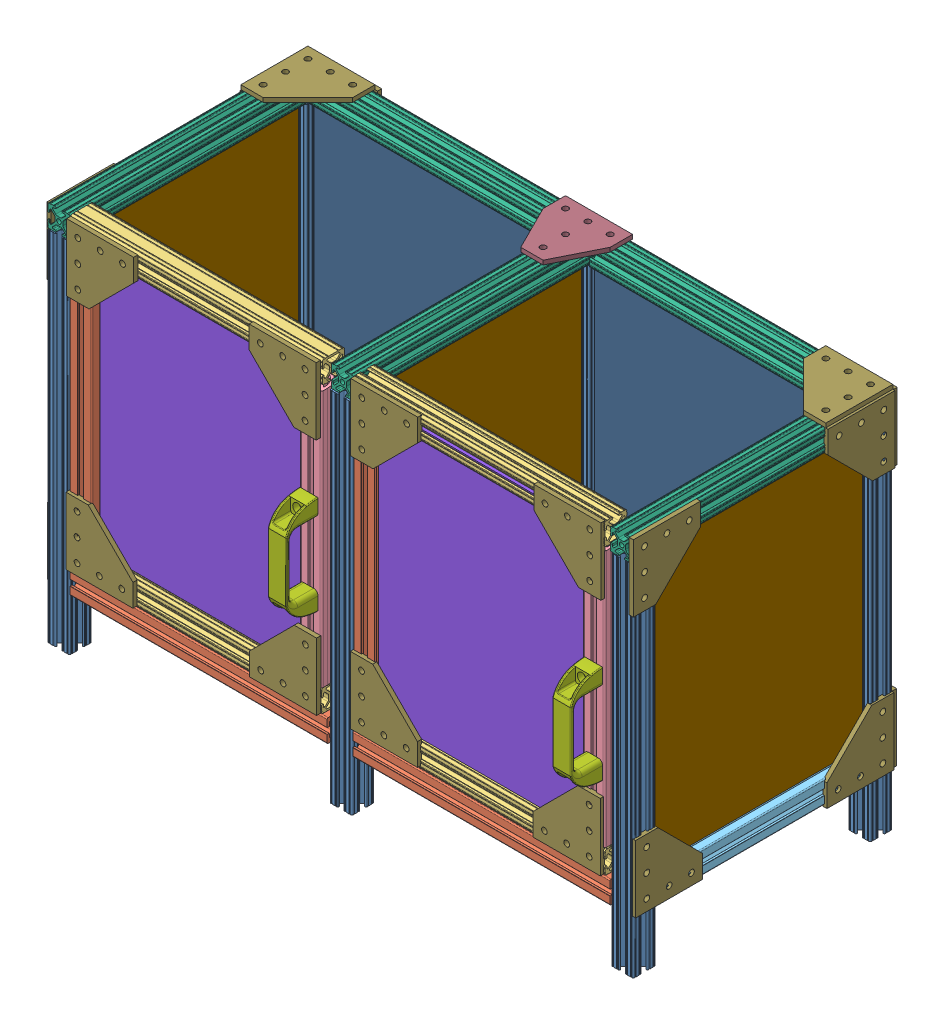
SolidWorks assembly Box_Ext_6_25_2024_Duplex, configuration Default. Lengths in mm.
Overall size (666.64 439.32 339.39).
68 component instances, 13 part files, 0 mates.
Components (placement in the parent):
- 1A_1D_16in47065T801_T-Slotted Framing rail-1: 1A_1D_16in47065T801_T-Slotted Framing rail [47065T801] at (-239.4342 265.817 193.973) x (0 0 1) z (0 1 0) size (25.4 25.4 406.4)
- 1A_1D_16in47065T801_T-Slotted Framing rail-2: 1A_1D_16in47065T801_T-Slotted Framing rail [47065T801] at (-240.0711 265.9257 462.8579) x (1 0 0) z (0 -1 0) size (25.4 25.4 406.4)
- 1A_1D_16in47065T801_T-Slotted Framing rail-3: 1A_1D_16in47065T801_T-Slotted Framing rail [47065T801] at (79.5241 264.9055 193.6515) x (1 0 0) z (0 -1 0) size (25.4 25.4 406.4)
- 1A_1D_16in47065T801_T-Slotted Framing rail-4: 1A_1D_16in47065T801_T-Slotted Framing rail [47065T801] at (79.0395 264.9055 462.2875) x (1 0 0) z (0 -1 0) size (25.4 25.4 406.4)
- 3A_3B_3C_11_5in6575N217_T-Slotted Framing Rail-1: 3A_3B_3C_11_5in6575N217_T-Slotted Framing Rail [6575N217] at (-80.5158 133.3354 462.6399) x (0 0 1) z (1 0 0) size (25.4 25.4 292.1)
- 5A_5B_11_25in_47065T846_T-Slotted Framing-1: 5A_5B_11_25in_47065T846_T-Slotted Framing [47065T846] at (-83.0751 159.6001 462.6399) x (0 0 1) z (-1 0 0) size (25.4 25.4 285.75)
- 3A_3B_3C_11_5in6575N217_T-Slotted Framing Rail-2: 3A_3B_3C_11_5in6575N217_T-Slotted Framing Rail [6575N217] at (-213.4294 321.0324 462.7499) x (1 0 0) z (0 -1 0) size (25.4 25.4 292.1)
- 6_11_5in6575N218_T-Slotted Framing Rail-1: 6_11_5in6575N218_T-Slotted Framing Rail [6575N218] at (46.9584 319.918 462.4695) x (0 1 0) z (1 0 0) size (292.1 25.4 25.4)
- 5A_5B_11_25in_47065T846_T-Slotted Framing-2: 5A_5B_11_25in_47065T846_T-Slotted Framing [47065T846] at (-83.4418 482.5282 462.8007) x (0 1 0) z (1 0 0) size (25.4 25.4 285.75)
- 2A_2B_9_5in6575N217_T-Slotted Framing Rail-1: 2A_2B_9_5in6575N217_T-Slotted Framing Rail [6575N217] at (78.5396 136.1503 326.476) size (25.4 25.4 241.3)
- 2A_2B_9_5in6575N217_T-Slotted Framing Rail-2: 2A_2B_9_5in6575N217_T-Slotted Framing Rail [6575N217] at (-239.3609 136.2243 327.8144) x (0 1 0) z (0 0 1) size (25.4 25.4 241.3)
- 3A_3B_3C_11_5in6575N217_T-Slotted Framing Rail-3: 3A_3B_3C_11_5in6575N217_T-Slotted Framing Rail [6575N217] at (-81.1923 133.366 194.3443) x (0 0.008727 0.999962) z (-1 0 0) size (25.4 25.4 292.1)
- 4A_4C_11_5in47065T801_T-Slotted Framing rail-1: 4A_4C_11_5in47065T801_T-Slotted Framing rail [47065T801] at (-240.0375 481.9511 327.6131) size (25.4 25.4 292.1)
- 4A_4C_11_5in47065T801_T-Slotted Framing rail-2: 4A_4C_11_5in47065T801_T-Slotted Framing rail [47065T801] at (77.9867 481.0907 328.468) size (25.4 25.4 292.1)
- 4A_4C_11_5in47065T801_T-Slotted Framing rail-3: 4A_4C_11_5in47065T801_T-Slotted Framing rail [47065T801] at (-80.1705 480.6089 194.2481) x (0 1 0) z (1 0 0) size (25.4 25.4 292.1)
- 47065T595_Red Plastic Pull Handle-1: 47065T595_Red Plastic Pull Handle [47065T595] at (47.7995 342.8306 476.5075) x (-1 0 0) z (0 0 1) size (21.11 112.11 36)
- pD-1: pD [Default] at (39.7962 478.6241 471.804) x (-1 0 0) z (0 -1 0) size (250.83 4.76 304.8)
- pA-1: pA [Default] at (80.357 148.7713 200.6755) x (0 1 0) z (0 0 1) size (317.5 4.76 254)
- pA-2: pA [Default] at (-240.7265 149.3164 198.8892) x (0 1 0) z (0 0 1) size (317.5 4.76 254)
- pB-3: pB [Default] at (-237.6602 138.9797 195.7037) x (0 1 0) z (1 0 0) size (330.2 4.76 304.8)
- pE-1: pE [Default] at (-227.8794 132.6636 204.9097) size (50.8 4.76 254)
- pE-2: pE [Default] at (-164.9525 130.5241 208.5576) size (50.8 4.76 254)
- pE-3: pE [Default] at (-102.4815 131.3886 208.1017) size (50.8 4.76 254)
- pE-4: pE [Default] at (-41.8346 135.1169 204.9097) size (50.8 4.76 254)
- pE-5: pE [Default] at (16.0764 135.6961 203.9977) size (50.8 4.76 254)
- 47065T267_T-Slotted Framing-5: 47065T267_T-Slotted Framing [47065T267] at (-225.7817 150.6545 476.5665) size (76.2 76.2 4.76)
- 47065T267_T-Slotted Framing-6: 47065T267_T-Slotted Framing [47065T267] at (-225.4278 495.4606 476.5665) x (1 0 0) z (0 0 -1) size (76.2 76.2 4.76)
- 47065T267_T-Slotted Framing-7: 47065T267_T-Slotted Framing [47065T267] at (58.1546 147.8233 476.5665) x (-1 0 0) z (0 0 -1) size (76.2 76.2 4.76)
- 47065T267_T-Slotted Framing-8: 47065T267_T-Slotted Framing [47065T267] at (58.8624 495.4606 476.5665) x (0 -1 0) z (0 0 -1) size (76.2 76.2 4.76)
- 47065T267_T-Slotted Framing-9: 47065T267_T-Slotted Framing [47065T267] at (91.7738 121.2891 181.2308) x (0 1 0) z (1 0 0) size (76.2 76.2 4.76)
- 47065T267_T-Slotted Framing-10: 47065T267_T-Slotted Framing [47065T267] at (91.7738 122.3717 474.8484) x (0 0 -1) z (1 0 0) size (76.2 76.2 4.76)
- 47065T267_T-Slotted Framing-11: 47065T267_T-Slotted Framing [47065T267] at (91.7738 493.9478 180.1367) x (0 0 1) z (1 0 0) size (76.2 76.2 4.76)
- 47065T267_T-Slotted Framing-12: 47065T267_T-Slotted Framing [47065T267] at (91.7738 495.7024 477.344) x (0 -1 0) z (1 0 0) size (76.2 76.2 4.76)
- 47065T267_T-Slotted Framing-14: 47065T267_T-Slotted Framing [47065T267] at (91.3964 120.9795 177.9621) x (-1 0 0) z (0 0 -1) size (76.2 76.2 4.76)
- 47065T267_T-Slotted Framing-16: 47065T267_T-Slotted Framing [47065T267] at (92.1046 493.9024 177.9621) x (-1 0 0) z (0 0 1) size (76.2 76.2 4.76)
- 4A_4C_11_5in47065T801_T-Slotted Framing rail-4: 4A_4C_11_5in47065T801_T-Slotted Framing rail [47065T801] at (-399.0464 482.3587 194.4736) x (0 0 -1) z (1 0 0) size (25.4 25.4 292.1)
- 4A_4C_11_5in47065T801_T-Slotted Framing rail-5: 4A_4C_11_5in47065T801_T-Slotted Framing rail [47065T801] at (-558.1373 482.8226 331.5399) size (25.4 25.4 292.1)
- 3A_3B_3C_11_5in6575N217_T-Slotted Framing Rail-4: 3A_3B_3C_11_5in6575N217_T-Slotted Framing Rail [6575N217] at (-398.4723 134.0137 195.5798) x (0 0 -1) z (-1 0 0) size (25.4 25.4 292.1)
- 3A_3B_3C_11_5in6575N217_T-Slotted Framing Rail-5: 3A_3B_3C_11_5in6575N217_T-Slotted Framing Rail [6575N217] at (-398.8921 134.4335 465.566) x (0 0 -1) z (-1 0 0) size (25.4 25.4 292.1)
- 2A_2B_9_5in6575N217_T-Slotted Framing Rail-3: 2A_2B_9_5in6575N217_T-Slotted Framing Rail [6575N217] at (-557.1339 134.4335 331.1914) x (1 0 0) z (0 0 -1) size (25.4 25.4 241.3)
- 1A_1D_16in47065T801_T-Slotted Framing rail-5: 1A_1D_16in47065T801_T-Slotted Framing rail [47065T801] at (-558.2613 266.406 196.6909) x (0 0 -1) z (0 1 0) size (25.4 25.4 406.4)
- 1A_1D_16in47065T801_T-Slotted Framing rail-6: 1A_1D_16in47065T801_T-Slotted Framing rail [47065T801] at (-558.2613 265.9621 465.316) x (0 0 1) z (0 1 0) size (25.4 25.4 406.4)
- 5A_5B_11_25in_47065T846_T-Slotted Framing-3: 5A_5B_11_25in_47065T846_T-Slotted Framing [47065T846] at (-402.1574 160.4493 465.566) x (0 0 1) z (-1 0 0) size (25.4 25.4 285.75)
- 3A_3B_3C_11_5in6575N217_T-Slotted Framing Rail-6: 3A_3B_3C_11_5in6575N217_T-Slotted Framing Rail [6575N217] at (-531.9495 322.4768 466.5987) x (-1 0 0) z (0 1 0) size (25.4 25.4 292.1)
- 6_11_5in6575N218_T-Slotted Framing Rail-2: 6_11_5in6575N218_T-Slotted Framing Rail [6575N218] at (-272.0186 319.0325 465.0526) x (0 -1 0) z (0 0 -1) size (292.1 25.4 25.4)
- 5A_5B_11_25in_47065T846_T-Slotted Framing-4: 5A_5B_11_25in_47065T846_T-Slotted Framing [47065T846] at (-402.3423 483.165 464.4355) x (0 0 1) z (1 0 0) size (25.4 25.4 285.75)
- pD-2: pD [Default] at (-274.4888 166.647 461.6473) x (-1 0 0) z (0 1 0) size (250.83 4.76 304.8)
- pA-3: pA [Default] at (-554.1224 464.9141 452.6716) x (0 -1 0) z (0 0 -1) size (317.5 4.76 254)
- pB-4: pB [Default] at (-552.971 143.2769 191.2421) x (0 1 0) z (1 0 0) size (330.2 4.76 304.8)
- pE-6: pE [Default] at (-546.4363 124.5592 202.1402) size (50.8 4.76 254)
- pE-7: pE [Default] at (-487.6728 124.5592 206.3376) size (50.8 4.76 254)
- pE-8: pE [Default] at (-425.971 124.5592 206.7574) size (50.8 4.76 254)
- pE-9: pE [Default] at (-365.5285 124.5592 205.9179) size (50.8 4.76 254)
- pE-10: pE [Default] at (-303.8268 125.4542 203.8192) size (50.8 4.76 254)
- 47065T595_Red Plastic Pull Handle-2: 47065T595_Red Plastic Pull Handle [47065T595] at (-272.9702 257.0099 478.9717) size (21.11 112.11 36)
- 47065T267_T-Slotted Framing-17: 47065T267_T-Slotted Framing [47065T267] at (-545.2849 149.3919 480.2384) size (76.2 76.2 4.76)
- 47065T267_T-Slotted Framing-18: 47065T267_T-Slotted Framing [47065T267] at (-260.4721 148.1315 480.2384) x (-1 0 0) z (0 0 -1) size (76.2 76.2 4.76)
- 47065T267_T-Slotted Framing-19: 47065T267_T-Slotted Framing [47065T267] at (-544.4454 495.0647 480.2384) x (1 0 0) z (0 0 -1) size (76.2 76.2 4.76)
- 47065T267_T-Slotted Framing-20: 47065T267_T-Slotted Framing [47065T267] at (-260.894 495.0647 480.2384) x (0 -1 0) z (0 0 -1) size (76.2 76.2 4.76)
- 47065T267_T-Slotted Framing-21: 47065T267_T-Slotted Framing [47065T267] at (-570.101 122.4814 476.0409) x (0 0 -1) z (1 0 0) size (76.2 76.2 4.76)
- 47065T267_T-Slotted Framing-22: 47065T267_T-Slotted Framing [47065T267] at (-570.101 122.1135 180.3849) x (0 1 0) z (1 0 0) size (76.2 76.2 4.76)
- 47065T267_T-Slotted Framing-23: 47065T267_T-Slotted Framing [47065T267] at (-570.101 494.6177 181.4893) x (0 -1 0) z (-1 0 0) size (76.2 76.2 4.76)
- 47065T267_T-Slotted Framing-24: 47065T267_T-Slotted Framing [47065T267] at (-570.101 494.6177 477.1041) x (0 0 -1) z (-1 0 0) size (76.2 76.2 4.76)
- 47065T267_T-Slotted Framing-25: 47065T267_T-Slotted Framing [47065T267] at (-569.5206 122.3098 178.5493) size (76.2 76.2 4.76)
- 47065T267_T-Slotted Framing-26: 47065T267_T-Slotted Framing [47065T267] at (-569.0988 495.3925 178.5493) x (1 0 0) z (0 0 -1) size (76.2 76.2 4.76)
- 47065T278_T-Slotted Framing-1: 47065T278_T-Slotted Framing [47065T278] at (-278.5261 497.8223 181.8044) x (1 0 0) z (0 -1 0) size (76.2 76.2 4.76)
- 47065T267_T-Slotted Framing-28: 47065T267_T-Slotted Framing [47065T267] at (-571.2013 498.6455 181.7368) x (1 0 0) z (0 -1 0) size (76.2 76.2 4.76)
- 47065T267_T-Slotted Framing-29: 47065T267_T-Slotted Framing [47065T267] at (92.4536 497.2034 180.8958) x (-1 0 0) z (0 1 0) size (76.2 76.2 4.76)
